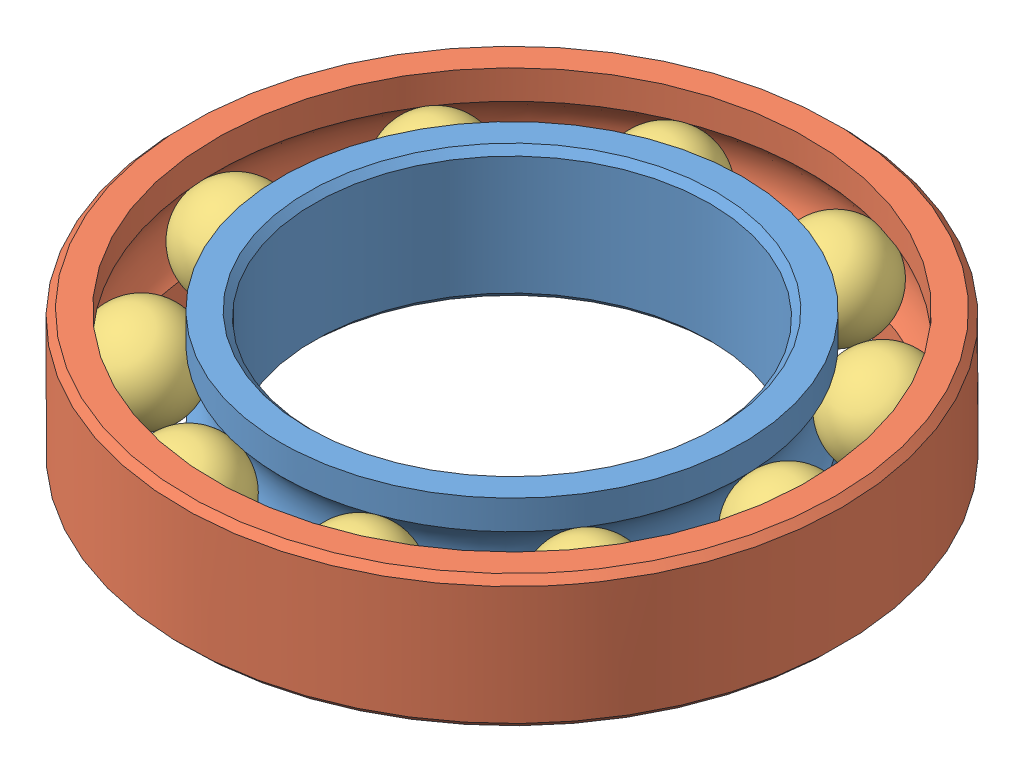
SolidWorks assembly Подшипник_1, configuration По умолчанию. Lengths in mm.
Overall size (14.01 2 14.01).
12 component instances, 3 part files, 3 mates.
Components (placement in the parent):
- Вн_кольцо-1: Вн_кольцо [По умолчанию] at origin size (7 2 7)
- Нар_кольцо-2: Нар_кольцо [По умолчанию] x (0.605705 0 -0.795689) z (0.795689 0 0.605705) size (10 2 10)
- Шарик-1: Шарик [По умолчанию] at (-3.9953 0 0.1946) size (1.5 1.5 1.5)
- Шарик-2: Шарик [По умолчанию] at (-3.3466 0 -2.1909) x (0.809017 0 0.587785) z (-0.587785 0 0.809017) size (1.5 1.5 1.5)
- Шарик-3: Шарик [По умолчанию] at (-1.4197 0 -3.7396) x (0.309017 0 0.951057) z (-0.951057 0 0.309017) size (1.5 1.5 1.5)
- Шарик-4: Шарик [По умолчанию] at (1.0495 0 -3.8599) x (-0.309017 0 0.951057) z (-0.951057 0 -0.309017) size (1.5 1.5 1.5)
- Шарик-5: Шарик [По умолчанию] at (3.1179 0 -2.5058) x (-0.809017 0 0.587785) z (-0.587785 0 -0.809017) size (1.5 1.5 1.5)
- Шарик-6: Шарик [По умолчанию] at (3.9953 0 -0.1946) x (-1 0 0) z (0 0 -1) size (1.5 1.5 1.5)
- Шарик-7: Шарик [По умолчанию] at (3.3466 0 2.1909) x (-0.809017 0 -0.587785) z (0.587785 0 -0.809017) size (1.5 1.5 1.5)
- Шарик-8: Шарик [По умолчанию] at (1.4197 0 3.7396) x (-0.309017 0 -0.951057) z (0.951057 0 -0.309017) size (1.5 1.5 1.5)
- Шарик-9: Шарик [По умолчанию] at (-1.0495 0 3.8599) x (0.309017 0 -0.951057) z (0.951057 0 0.309017) size (1.5 1.5 1.5)
- Шарик-10: Шарик [По умолчанию] at (-3.1179 0 2.5058) x (0.809017 0 -0.587785) z (0.587785 0 0.809017) size (1.5 1.5 1.5)
Mates (geometry in assembly coordinates):
- Концентричный1: concentric aligned: cylinder of Вн_кольцо-1 through (0 1 0) axis (0 -1 0) radius 3.5; cylinder of Нар_кольцо-2 through (0 1 0) axis (0 -1 0) radius 4.5
- Совпадение1: coincident aligned: plane of Вн_кольцо-1 through (0 0 0) normal (0 1 0); plane of Нар_кольцо-2
- Совпадение2: coincident: point of Шарик-1; circle of assembly
